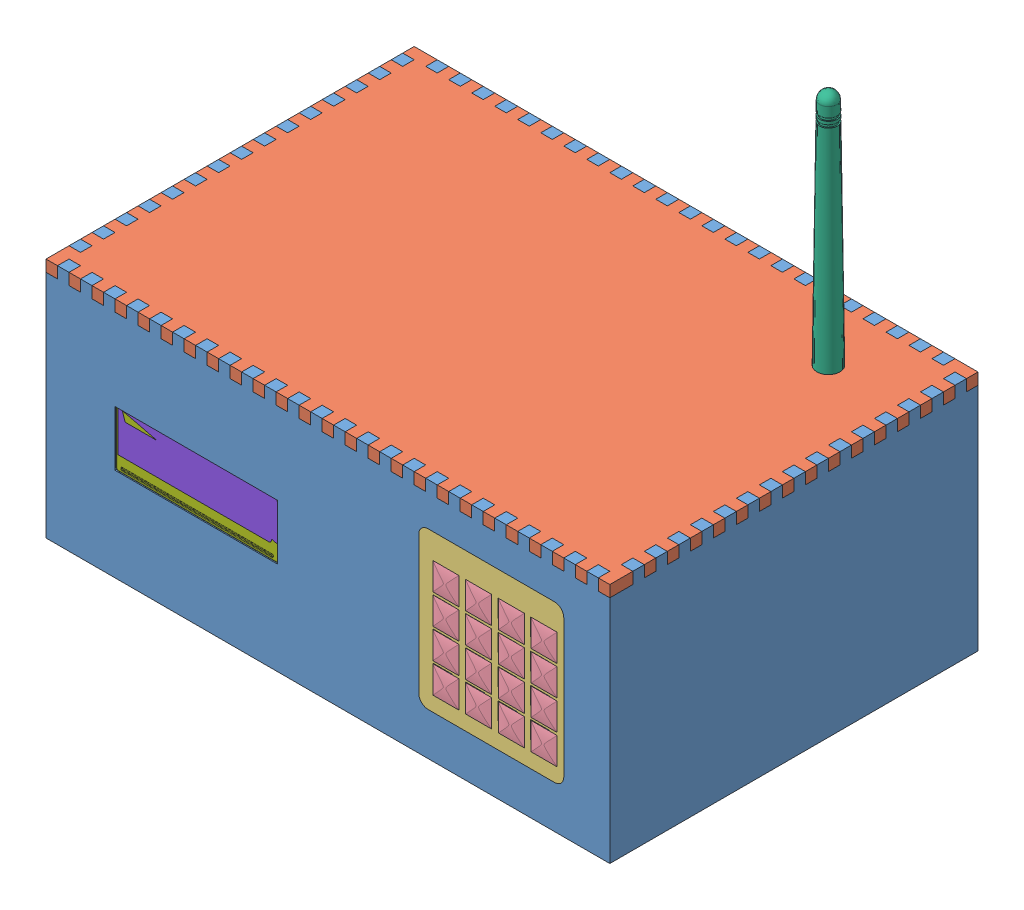
SolidWorks assembly box, configuration Predeterminado. Lengths in mm.
Overall size (245 208.75 166.76).
25 component instances, 8 part files, 21 mates.
Components (placement in the parent):
- box_base-1: box_base [Predeterminado] at (-78.8421 -11.754 100) size (245 105 160)
- box_tapa-1: box_tapa [Predeterminado] at (-78.8421 93.246 -60) x (1 0 0) z (0 0 -1) size (245 5 160)
- box_keypad-1: box_keypad [Default] at (131.0939 32.1171 90.6615) size (71 77.5 8.56)
  - plastic_base-1: plastic_base [Default] at (-16.436 8.6289 2.8107) size (71 77.5 6.53)
  - key-1: key [Default] at (-36.186 25.8429 9.3385) size (11.84 11.8 0.8)
  - key-2: key [Default] at (-36.186 12.8889 9.3385) size (11.84 11.8 0.8)
  - key-3: key [Default] at (-36.186 -0.0651 9.3385) size (11.84 11.8 0.8)
  - key-4: key [Default] at (-36.186 -13.0191 9.3385) size (11.84 11.8 0.8)
  - key-5: key [Default] at (-21.962 25.8429 9.3385) size (11.84 11.8 0.8)
  - key-6: key [Default] at (-21.962 12.8889 9.3385) size (11.84 11.8 0.8)
  - key-7: key [Default] at (-21.962 -0.0651 9.3385) size (11.84 11.8 0.8)
  - key-8: key [Default] at (-21.962 -13.0191 9.3385) size (11.84 11.8 0.8)
  - key-9: key [Default] at (-7.738 25.8429 9.3385) size (11.84 11.8 0.8)
  - key-10: key [Default] at (-7.738 12.8889 9.3385) size (11.84 11.8 0.8)
  - key-11: key [Default] at (-7.738 -0.0651 9.3385) size (11.84 11.8 0.8)
  - key-12: key [Default] at (-7.738 -13.0191 9.3385) size (11.84 11.8 0.8)
  - key-13: key [Default] at (6.486 25.8429 9.3385) size (11.84 11.8 0.8)
  - key-14: key [Default] at (6.486 12.8889 9.3385) size (11.84 11.8 0.8)
  - key-15: key [Default] at (6.486 -0.0651 9.3385) size (11.84 11.8 0.8)
  - key-16: key [Default] at (6.486 -13.0191 9.3385) size (11.84 11.8 0.8)
- box_cables-1: box_cables [Default] at (40.7759 8.8468 -45.3318) size (6.8 4.1 19.4)
- box_cables-7: box_cables [Default] at (44.3312 12.9359 -45.3318) size (6.8 4.1 19.4)
- box_antena-1: box_antena [Predeterminado] at (131.1579 93.246 -30) size (10 103.75 10)
- box_lcd-1: box_lcd [Default] at (-13.1921 42.146 99.2) x (1 0 0) z (0 -1 0) size (71.3 11.8 27.44)
- box_backlight-1: box_backlight [Default] at (-12.9921 44.246 97.7) x (1 0 0) z (0 -1 0) size (74.38 2.98 18)
Mates (geometry in assembly coordinates):
- Coincidente2: coincident anti-aligned: plane of box_base-1 through (-78.8421 -6.754 100) normal (0 0 1); plane of ? through (34.5086 39.5613 100) normal (0 0 -1)
- Coincidente3: coincident aligned: plane of box_base-1 through (-78.8421 -6.754 100) normal (-1 0 0); plane of box_tapa-1 through (-78.8421 88.246 90) normal (-1 0 0)
- Coincidente4: coincident aligned: plane of box_base-1 through (-78.8421 -6.754 100) normal (0 0 1); plane of box_tapa-1 through (-78.8421 88.246 100) normal (0 0 1)
- Coincidente7: coincident anti-aligned: plane of box_base-1 through (-48.8421 52.746 90) normal (0 -1 0); plane of ? through (-13.9921 52.746 99.2) normal (0 1 0)
- Coincidente8: coincident anti-aligned: plane of box_base-1 through (21.6579 52.746 90) normal (-1 0 0); plane of ? through (21.6579 30.746 97.2) normal (1 0 0)
- Coincidente10: coincident aligned: plane of box_base-1 through (-78.8421 -6.754 100) normal (0 0 1); plane of ? through (-13.9921 39.346 100) normal (0 0 1)
- Coincidente11: coincident anti-aligned: plane of box_base-1 through (83.1579 6.746 90) normal (0 1 0); plane of box_keypad-1/plastic_base-1 through (87.1579 6.746 100) normal (0 -1 0)
- Coincidente13: coincident aligned: plane of box_base-1 through (-78.8421 -6.754 100) normal (0 0 1); plane of box_keypad-1/plastic_base-1 through (87.1579 70.746 100) normal (0 0 1)
- Coincidente14: coincident anti-aligned: plane of box_base-1 through (146.1579 74.746 90) normal (-1 0 0); plane of box_keypad-1/plastic_base-1 through (146.1579 70.746 100) normal (1 0 0)
- Coincidente15: coincident aligned: plane of box_cables-1 through (40.7759 8.8468 -64.7318) normal (0 0 -1); plane of box_cables-7 through (44.3312 12.9359 -64.7318) normal (0 0 -1)
- Coincidente16: coincident anti-aligned: plane of box_base-1 through (-78.8421 88.246 100) normal (0 1 0); plane of box_tapa-1 through (-78.8421 88.246 -60) normal (0 -1 0)
- Coincidente17: coincident anti-aligned: circle of box_tapa-1; circle of box_antena-1
- Coincidente18: coincident anti-aligned: plane of box_base-1 through (-48.8421 28.746 90) normal (0 1 0); plane of box_lcd-1 through (-13.1921 28.746 99.2) normal (0 -1 0)
- Coincidente20: coincident anti-aligned: plane of box_base-1 through (-48.8421 52.746 90) normal (1 0 0); plane of box_lcd-1 through (-48.8421 50.746 97.2) normal (-1 0 0)
- Coincidente21: coincident: plane of box_base-1 through (-78.8421 -6.754 100) normal (0 0 1); line of box_lcd-1 through (19.3079 52.846 100) axis (-1 0 0)
- Coincidente22: coincident aligned: plane of box_base-1 through (-78.8421 -6.754 100) normal (0 0 1); plane of ? through (20.6579 52.246 100) normal (0 0 1)
- Coincidente23: coincident anti-aligned: plane of box_lcd-1 through (-44.4421 35.246 100) normal (0 1 0); plane of ? through (-47.6421 35.246 97.7) normal (0 -1 0)
- Coincidente24: coincident anti-aligned: plane of box_base-1 through (21.6579 52.746 90) normal (-1 0 0); plane of ? through (21.6579 36.246 97.7) normal (1 0 0)
- Coincidente25: coincident anti-aligned: plane of box_lcd-1 through (-44.4421 35.246 100) normal (0 1 0); plane of box_backlight-1 through (-47.6421 35.246 100) normal (0 -1 0)
- Coincidente26: coincident anti-aligned: plane of box_base-1 through (21.6579 52.746 90) normal (-1 0 0); plane of box_backlight-1 through (21.6579 52.246 100) normal (1 0 0)
- Coincidente27: coincident aligned: plane of box_base-1 through (-78.8421 -6.754 100) normal (0 0 1); plane of box_backlight-1 through (20.6579 36.246 100) normal (0 0 1)
